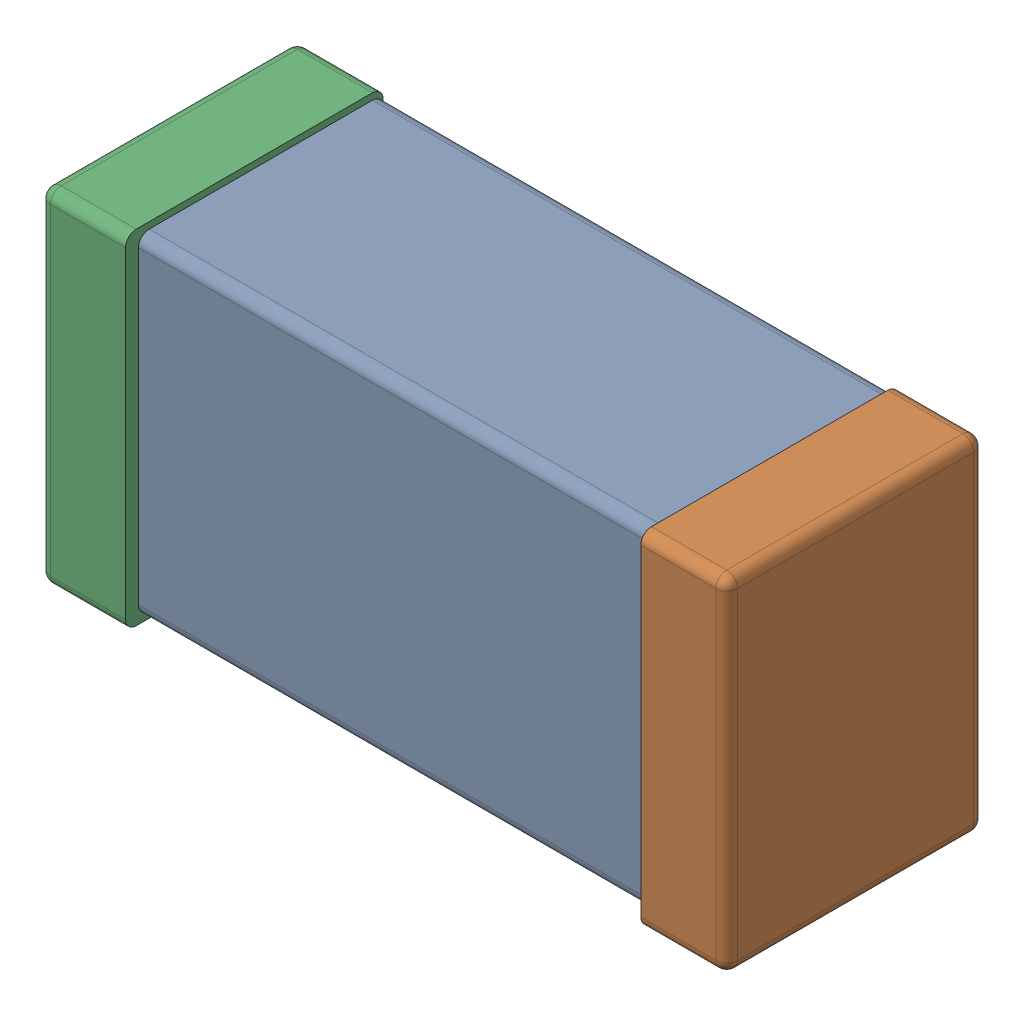
SolidWorks assembly C0603_060_4, configuration Standard. Lengths in mm.
Overall size (1.6 0.8 0.6).
4 component instances, 3 part files, 0 mates.
Components (placement in the parent):
- C0603_060_5-1: C0603_060_5 [Standard] at (0 0 23.8) size (1.6 0.8 0.6)
  - Part 3_1-1: Part 3_1 [Standard] at (0 0 -23.815) size (1.4 0.77 0.57)
  - Part 2_1-1: Part 2_1 [Standard] at (0 0 -23.8) size (0.2 0.8 0.6)
  - Part 1_1-1: Part 1_1 [Standard] at (0 0 -23.8) size (0.2 0.8 0.6)
